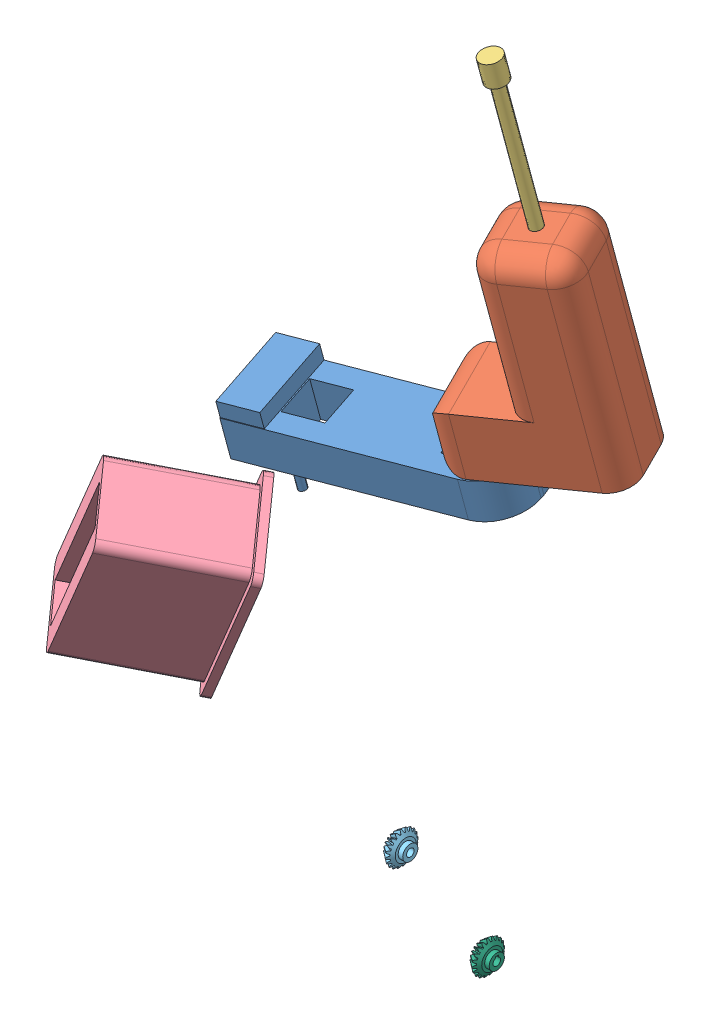
SolidWorks assembly Assemble Test, configuration Default. Lengths in mm.
Overall size (733.05 1023.39 260.93).
6 component instances, 6 part files, 2 mates.
Components (placement in the parent):
- Arm1-1: Arm1 [Default] at (-254.7679 483.8799 -419.095) x (0.973188 0.134625 -0.186499) z (0.207875 -0.167707 0.963671) size (320 140 105)
- Arm2-1: Arm2 [Default] at (-90.425 559.0216 -456.7672) x (0.916895 0.163703 -0.364012) z (0.386794 -0.139467 0.911559) size (200 340 105)
- Arm3-1: Arm3 [Default] at (-95.3168 1014.9148 -384.9408) x (0.227431 -0.164962 0.95972) z (0.968804 0.137975 -0.205868) size (27 330 27)
- Base2-1: Base2 [Default] at (-515.9521 194.5443 -456.1176) x (0.447868 0.883176 0.139337) z (0.583155 -0.406674 0.70324) size (230 160 125)
- PinionGear-1: PinionGear [Default] at (-217.7823 77.7128 -383.3018) size (43.33 43.31 43.29)
- PinionGear With Key-1: PinionGear With Key [Default] at (-67.4942 46.557 -346.971) size (43.33 43.31 43.29)
Mates (geometry in assembly coordinates):
- Coincident10: coincident anti-aligned: plane of Arm1-1 through (-259.6907 532.71 -409.5352) normal (-0.098457 0.976602 0.191195); plane of Arm2-1 through (-90.425 559.0216 -456.7672) normal (0.098457 -0.976602 -0.191195)
- Concentric24: concentric anti-aligned: cylinder of Arm2-1 through (-57.9582 644.3526 -457.4881) axis (0.098457 -0.976602 -0.191195) radius 7.75; cylinder of Arm3-1 through (-65.7797 721.9344 -442.2994) axis (-0.098457 0.976602 0.191195) radius 7.75
